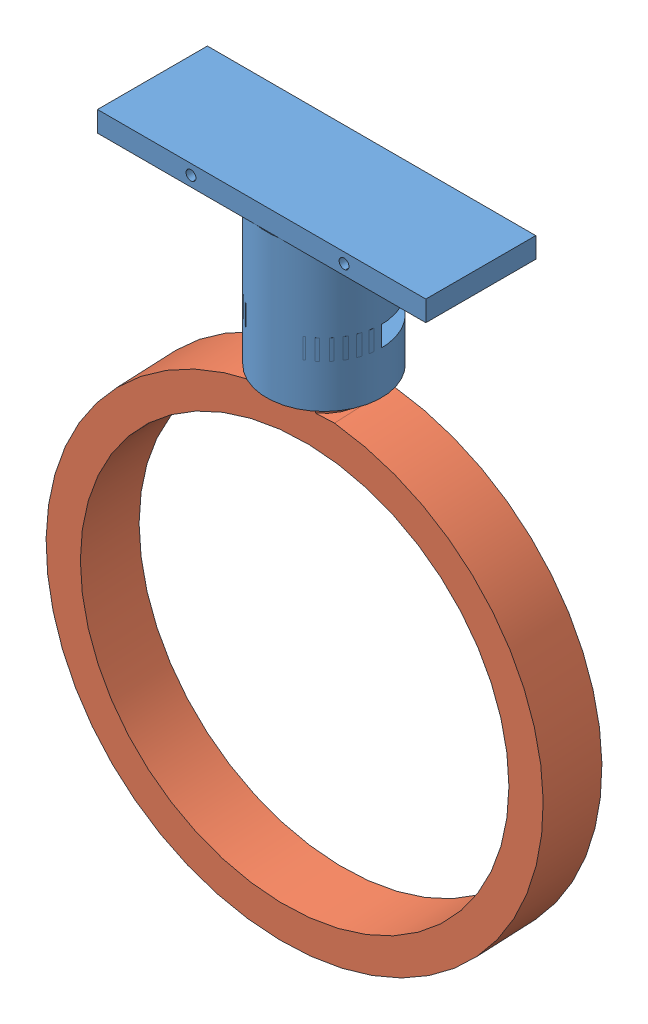
SolidWorks assembly VacuumFasten_002, configuration Default. Lengths in mm.
Overall size (74.06 101.12 17.16).
2 component instances, 2 part files, 2 mates.
Components (placement in the parent):
- VacuumCuff-1: VacuumCuff [Default] at (21.3144 4.595 30.4199) size (50.8 25.4 17.16)
- VacuumRing-1: VacuumRing [Default] at (21.0991 -34.2992 25.6623) x (0.998978 0 -0.045209) z (0.045209 0 0.998978) size (73.66 92.23 10.43)
Mates (geometry in assembly coordinates):
- Concentric1: concentric aligned: circle of VacuumCuff-1; circle of VacuumRing-1
- LimitDistance2: limit distance = 0 mm anti-aligned: plane of VacuumRing-1 through (21.3144 21.105 30.4199) normal (0 1 0); plane of VacuumCuff-1 through (21.3144 21.105 30.4199) normal (0 -1 0)
